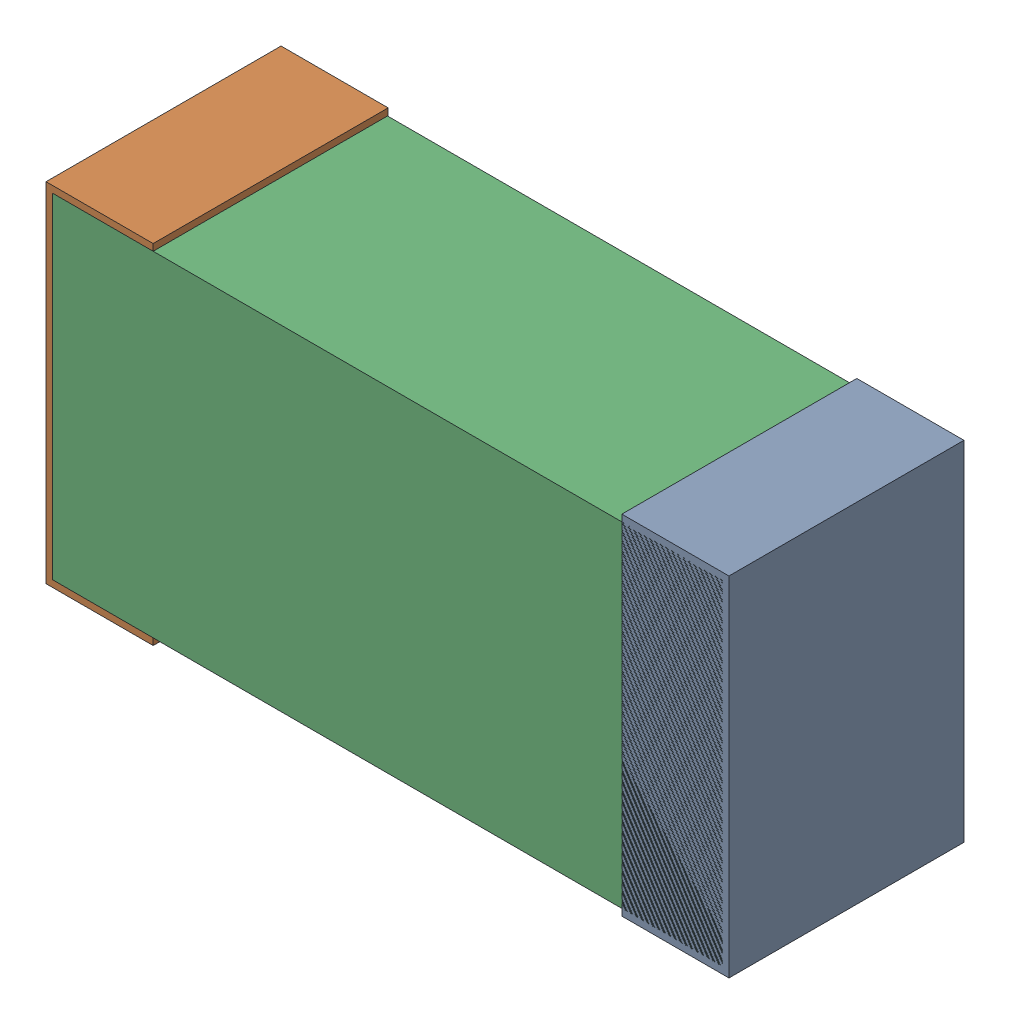
SolidWorks assembly C27, configuration Default. Lengths in mm.
Overall size (1.02 0.52 0.35).
6 component instances, 2 part files, 0 mates.
Components (placement in the parent):
- 870940480-1: 870940480 [Default] at (10.0685 26.617 -1.9516) size (0.16 0.52 0.35)
  - Extruded-1: Extruded [Default] at origin size (0.16 0.52 0.35)
- 870940480-2: 870940480 [Default] at (9.2085 26.617 -1.9516) size (0.16 0.52 0.35)
  - Extruded-1: Extruded [Default] at origin size (0.16 0.52 0.35)
- 870940640-1: 870940640 [Default] at (9.6385 26.617 -1.9506) size (1 0.5 0.35)
  - Extruded_2-1: Extruded_2 [Default] at origin size (1 0.5 0.35)
